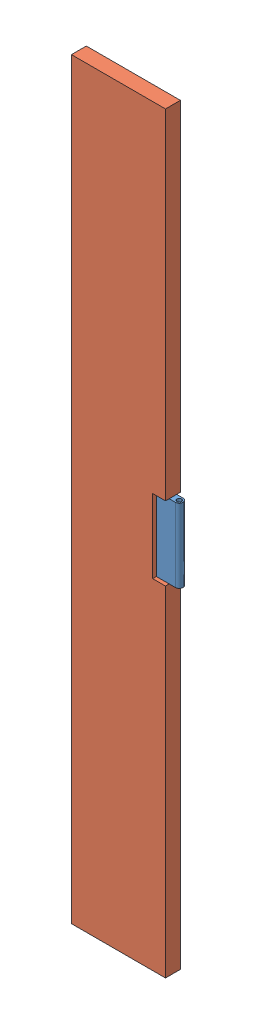
SolidWorks assembly ElevatorAssembly, configuration Default. Lengths in mm.
Overall size (1359.35 500 107.34).
2 component instances, 2 part files, 5 mates.
Components (placement in the parent):
- Elevator_to_Tail-3: Elevator_to_Tail [Default] at (-1299 0 99.89) x (0 -1 0) z (0 0 1) size (49 15.2 5)
- Elevator-2: Elevator [Default] at (-1328.1 0 97.44) x (0 -1 0) z (0 0 1) size (500 62.5 9.9)
Mates (geometry in assembly coordinates):
- Coincident1: coincident anti-aligned: plane of Elevator_to_Tail-3 through (-37.7479 -17.2751 8.295) normal (-1 0 0); plane of Elevator-2 through (-37.7479 -17.2751 0.845) normal (1 0 0)
- Width1: width anti-aligned: plane of Elevator_to_Tail-3 through (-31.3979 -41.7751 8.295) normal (0 0 1); plane of Elevator-2 through (-31.3979 -41.7751 3.295) normal (0 0 -1); plane of Elevator_to_Tail-3 through (-60.4979 -41.7751 0.845) normal (0 0 -1); plane of Elevator-2 through (-60.4979 -41.7751 10.745) normal (0 0 1)
- Width2: width anti-aligned: plane of Elevator_to_Tail-3 through (-25.0479 -66.2751 8.295) normal (0 -1 0); plane of Elevator-2 through (-25.0479 -17.2751 8.295) normal (0 1 0); plane of Elevator_to_Tail-3 through (-20.7479 -66.2751 0.845) normal (0 1 0); plane of Elevator-2 through (-20.7479 -17.2751 0.845) normal (0 -1 0)
- Width3: width aligned: plane of Elevator-2 through (-60.4979 -41.7751 0.845) normal (0 0 -1); plane of Elevator_to_Tail-3 through (-60.4979 -41.7751 10.745) normal (0 0 1); plane of Elevator-2 through (-31.3979 -41.7751 3.295) normal (0 0 -1); plane of Elevator_to_Tail-3 through (-31.3979 -41.7751 8.295) normal (0 0 1)
- Coincident2: coincident: unknown of Elevator_to_Tail-3
